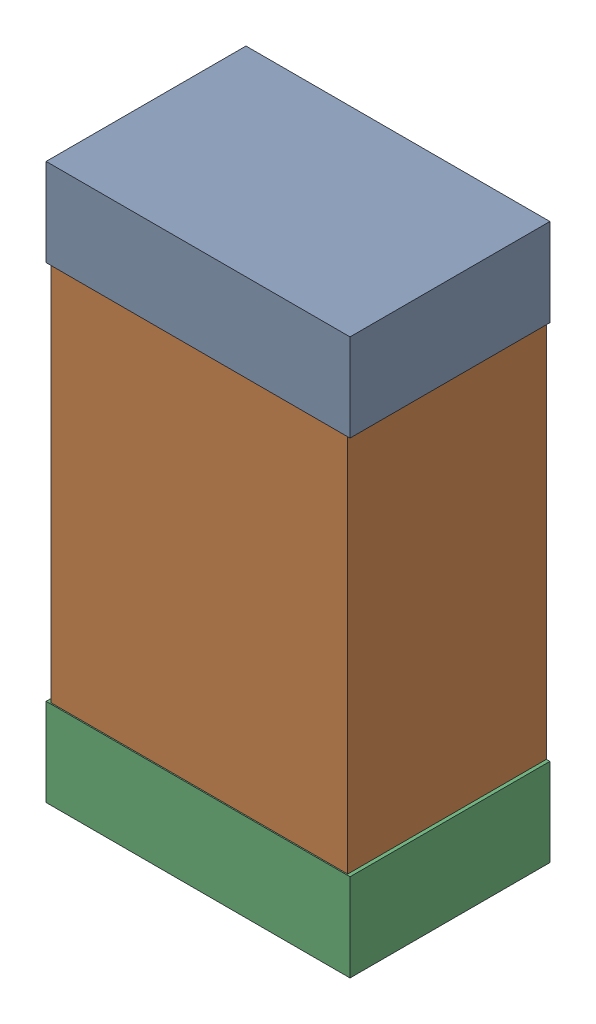
SolidWorks assembly C3Kanaloa_v2.0.0_GPIO_b, configuration Default. Lengths in mm.
Overall size (1.3 2.38 0.85).
6 component instances, 2 part files, 0 mates.
Components (placement in the parent):
- 330415056-1: 330415056 [Default] at (85.852 77.327 0) size (1.3 0.38 0.85)
  - Extruded_2-1: Extruded_2 [Default] at origin size (1.3 0.38 0.85)
- 352877008-1: 352877008 [Default] at (85.852 76.327 0) size (1.27 2.2 0.85)
  - Extruded_3-1: Extruded_3 [Default] at origin size (1.27 2.2 0.85)
- 330415056-2: 330415056 [Default] at (85.852 75.327 0) size (1.3 0.38 0.85)
  - Extruded_2-1: Extruded_2 [Default] at origin size (1.3 0.38 0.85)
